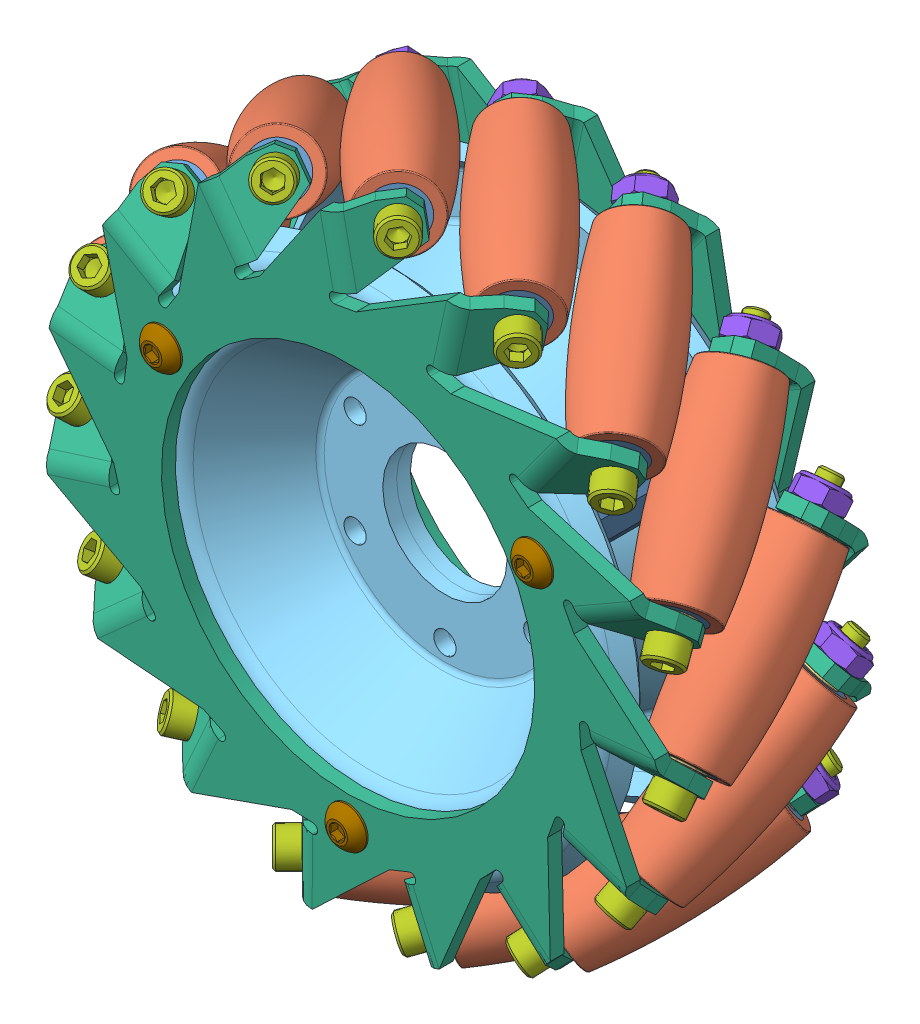
SolidWorks assembly BASE-Mecanum Wheel RIGHT, configuration Default. Lengths in mm.
Overall size (162 161.21 55.95).
134 component instances, 10 part files, 0 mates.
Components (placement in the parent):
- am-3479Ra 6 SR Mecanum Right with Standoffs.STEP-1: am-3479Ra 6 SR Mecanum Right with Standoffs.STEP [Default] at origin size (162 161.21 55.95)
  - am-3479_roller.STEP-1: am-3479_roller.STEP [Default] at (29.7299 -60.2636 1.1233) x (0.762257 -0.31184 0.567204) z (-0.055951 -0.90476 -0.422232) size (19.48 44.35 19.48)
    - am-3698_core PC.STEP-1: am-3698_core PC.STEP [Default] at (-2.9239 1.0394 0.8367) size (14.92 43.18 14.92)
    - am-3698_skin TPU v2.STEP-1: am-3698_skin TPU v2.STEP [Default] at (-2.9239 22.6294 0.8367) x (1 0 0) z (0 1 0) size (19.48 19.48 43.18)
    - am-0603 MBC Bushing MU04TH04.STEP-1: am-0603 MBC Bushing MU04TH04.STEP [Default] at (-2.9239 -20.9316 0.8367) x (0 1 0) z (0 0 1) size (6.35 7.94 7.94)
    - am-0603 MBC Bushing MU04TH04.STEP-2: am-0603 MBC Bushing MU04TH04.STEP [Default] at (-2.9239 16.6604 0.8367) x (0 1 0) z (-0.707574 0 0.70664) size (6.35 7.94 7.94)
    - am-0701a 6IN SR Roller Axle.STEP-1: am-0701a 6IN SR Roller Axle.STEP [Default] at (-2.9239 23.2136 0.8367) x (0 -1 0) z (0 0 1) size (44.35 6.35 6.35)
  - am-3479_roller-1.STEP-1: am-3479_roller-1.STEP [Default] at (2.6482 -67.1458 1.1233) x (0.569519 -0.594918 0.567204) z (-0.419113 -0.803782 -0.422232) size (19.48 44.35 19.48)
    - am-3698_core PC.STEP-1: am-3698_core PC.STEP [Default] at (-2.9239 1.0394 0.8367) size (14.92 43.18 14.92)
    - am-3698_skin TPU v2.STEP-1: am-3698_skin TPU v2.STEP [Default] at (-2.9239 22.6294 0.8367) x (1 0 0) z (0 1 0) size (19.48 19.48 43.18)
    - am-0603 MBC Bushing MU04TH04.STEP-1: am-0603 MBC Bushing MU04TH04.STEP [Default] at (-2.9239 -20.9316 0.8367) x (0 1 0) z (0 0 1) size (6.35 7.94 7.94)
    - am-0603 MBC Bushing MU04TH04.STEP-2: am-0603 MBC Bushing MU04TH04.STEP [Default] at (-2.9239 16.6604 0.8367) x (0 1 0) z (-0.707574 0 0.70664) size (6.35 7.94 7.94)
    - am-0701a 6IN SR Roller Axle.STEP-1: am-0701a 6IN SR Roller Axle.STEP [Default] at (-2.9239 23.2136 0.8367) x (0 -1 0) z (0 0 1) size (44.35 6.35 6.35)
  - am-3479_roller-2.STEP-1: am-3479_roller-2.STEP [Default] at (-24.8914 -62.4179 1.1233) x (0.278307 -0.775129 0.567204) z (-0.709806 -0.563823 -0.422232) size (19.48 44.35 19.48)
    - am-3698_core PC.STEP-1: am-3698_core PC.STEP [Default] at (-2.9239 1.0394 0.8367) size (14.92 43.18 14.92)
    - am-3698_skin TPU v2.STEP-1: am-3698_skin TPU v2.STEP [Default] at (-2.9239 22.6294 0.8367) x (1 0 0) z (0 1 0) size (19.48 19.48 43.18)
    - am-0603 MBC Bushing MU04TH04.STEP-1: am-0603 MBC Bushing MU04TH04.STEP [Default] at (-2.9239 -20.9316 0.8367) x (0 1 0) z (0 0 1) size (6.35 7.94 7.94)
    - am-0603 MBC Bushing MU04TH04.STEP-2: am-0603 MBC Bushing MU04TH04.STEP [Default] at (-2.9239 16.6604 0.8367) x (0 1 0) z (-0.707574 0 0.70664) size (6.35 7.94 7.94)
    - am-0701a 6IN SR Roller Axle.STEP-1: am-0701a 6IN SR Roller Axle.STEP [Default] at (-2.9239 23.2136 0.8367) x (0 -1 0) z (0 0 1) size (44.35 6.35 6.35)
  - am-3479_roller-3.STEP-1: am-3479_roller-3.STEP [Default] at (-48.1271 -46.8973 1.1233) x (-0.061028 -0.821313 0.567204) z (-0.877767 -0.226374 -0.422232) size (19.48 44.35 19.48)
    - am-3698_core PC.STEP-1: am-3698_core PC.STEP [Default] at (-2.9239 1.0394 0.8367) size (14.92 43.18 14.92)
    - am-3698_skin TPU v2.STEP-1: am-3698_skin TPU v2.STEP [Default] at (-2.9239 22.6294 0.8367) x (1 0 0) z (0 1 0) size (19.48 19.48 43.18)
    - am-0603 MBC Bushing MU04TH04.STEP-1: am-0603 MBC Bushing MU04TH04.STEP [Default] at (-2.9239 -20.9316 0.8367) x (0 1 0) z (0 0 1) size (6.35 7.94 7.94)
    - am-0603 MBC Bushing MU04TH04.STEP-2: am-0603 MBC Bushing MU04TH04.STEP [Default] at (-2.9239 16.6604 0.8367) x (0 1 0) z (-0.707574 0 0.70664) size (6.35 7.94 7.94)
    - am-0701a 6IN SR Roller Axle.STEP-1: am-0701a 6IN SR Roller Axle.STEP [Default] at (-2.9239 23.2136 0.8367) x (0 -1 0) z (0 0 1) size (44.35 6.35 6.35)
  - am-3479_roller-4.STEP-1: am-3479_roller-4.STEP [Default] at (-63.0411 -23.2678 1.1233) x (-0.38981 -0.725485 0.567204) z (-0.893955 0.150218 -0.422232) size (19.48 44.35 19.48)
    - am-3698_core PC.STEP-1: am-3698_core PC.STEP [Default] at (-2.9239 1.0394 0.8367) size (14.92 43.18 14.92)
    - am-3698_skin TPU v2.STEP-1: am-3698_skin TPU v2.STEP [Default] at (-2.9239 22.6294 0.8367) x (1 0 0) z (0 1 0) size (19.48 19.48 43.18)
    - am-0603 MBC Bushing MU04TH04.STEP-1: am-0603 MBC Bushing MU04TH04.STEP [Default] at (-2.9239 -20.9316 0.8367) x (0 1 0) z (0 0 1) size (6.35 7.94 7.94)
    - am-0603 MBC Bushing MU04TH04.STEP-2: am-0603 MBC Bushing MU04TH04.STEP [Default] at (-2.9239 16.6604 0.8367) x (0 1 0) z (-0.707574 0 0.70664) size (6.35 7.94 7.94)
    - am-0701a 6IN SR Roller Axle.STEP-1: am-0701a 6IN SR Roller Axle.STEP [Default] at (-2.9239 23.2136 0.8367) x (0 -1 0) z (0 0 1) size (44.35 6.35 6.35)
  - am-3479_roller-5.STEP-1: am-3479_roller-5.STEP [Default] at (-67.0548 4.385 1.1233) x (-0.65119 -0.504213 0.567204) z (-0.755569 0.500835 -0.422232) size (19.48 44.35 19.48)
    - am-3698_core PC.STEP-1: am-3698_core PC.STEP [Default] at (-2.9239 1.0394 0.8367) size (14.92 43.18 14.92)
    - am-3698_skin TPU v2.STEP-1: am-3698_skin TPU v2.STEP [Default] at (-2.9239 22.6294 0.8367) x (1 0 0) z (0 1 0) size (19.48 19.48 43.18)
    - am-0603 MBC Bushing MU04TH04.STEP-1: am-0603 MBC Bushing MU04TH04.STEP [Default] at (-2.9239 -20.9316 0.8367) x (0 1 0) z (0 0 1) size (6.35 7.94 7.94)
    - am-0603 MBC Bushing MU04TH04.STEP-2: am-0603 MBC Bushing MU04TH04.STEP [Default] at (-2.9239 16.6604 0.8367) x (0 1 0) z (-0.707574 0 0.70664) size (6.35 7.94 7.94)
    - am-0701a 6IN SR Roller Axle.STEP-1: am-0701a 6IN SR Roller Axle.STEP [Default] at (-2.9239 23.2136 0.8367) x (0 -1 0) z (0 0 1) size (44.35 6.35 6.35)
  - am-3479_roller-6.STEP-1: am-3479_roller-6.STEP [Default] at (-59.4741 31.2795 1.1233) x (-0.799974 -0.195759 0.567204) z (-0.486539 0.764853 -0.422232) size (19.48 44.35 19.48)
    - am-3698_core PC.STEP-1: am-3698_core PC.STEP [Default] at (-2.9239 1.0394 0.8367) size (14.92 43.18 14.92)
    - am-3698_skin TPU v2.STEP-1: am-3698_skin TPU v2.STEP [Default] at (-2.9239 22.6294 0.8367) x (1 0 0) z (0 1 0) size (19.48 19.48 43.18)
    - am-0603 MBC Bushing MU04TH04.STEP-1: am-0603 MBC Bushing MU04TH04.STEP [Default] at (-2.9239 -20.9316 0.8367) x (0 1 0) z (0 0 1) size (6.35 7.94 7.94)
    - am-0603 MBC Bushing MU04TH04.STEP-2: am-0603 MBC Bushing MU04TH04.STEP [Default] at (-2.9239 16.6604 0.8367) x (0 1 0) z (-0.707574 0 0.70664) size (6.35 7.94 7.94)
    - am-0701a 6IN SR Roller Axle.STEP-1: am-0701a 6IN SR Roller Axle.STEP [Default] at (-2.9239 23.2136 0.8367) x (0 -1 0) z (0 0 1) size (44.35 6.35 6.35)
  - am-3479_roller-7.STEP-1: am-3479_roller-7.STEP [Default] at (-41.6097 52.7655 1.1233) x (-0.810435 0.146544 0.567204) z (-0.133382 0.896621 -0.422232) size (19.48 44.35 19.48)
    - am-3698_core PC.STEP-1: am-3698_core PC.STEP [Default] at (-2.9239 1.0394 0.8367) size (14.92 43.18 14.92)
    - am-3698_skin TPU v2.STEP-1: am-3698_skin TPU v2.STEP [Default] at (-2.9239 22.6294 0.8367) x (1 0 0) z (0 1 0) size (19.48 19.48 43.18)
    - am-0603 MBC Bushing MU04TH04.STEP-1: am-0603 MBC Bushing MU04TH04.STEP [Default] at (-2.9239 -20.9316 0.8367) x (0 1 0) z (0 0 1) size (6.35 7.94 7.94)
    - am-0603 MBC Bushing MU04TH04.STEP-2: am-0603 MBC Bushing MU04TH04.STEP [Default] at (-2.9239 16.6604 0.8367) x (0 1 0) z (-0.707574 0 0.70664) size (6.35 7.94 7.94)
    - am-0701a 6IN SR Roller Axle.STEP-1: am-0701a 6IN SR Roller Axle.STEP [Default] at (-2.9239 23.2136 0.8367) x (0 -1 0) z (0 0 1) size (44.35 6.35 6.35)
  - am-3479_roller-8.STEP-1: am-3479_roller-8.STEP [Default] at (-16.5507 65.1279 1.1233) x (-0.680764 0.463508 0.567204) z (0.242838 0.873356 -0.422232) size (19.48 44.35 19.48)
    - am-3698_core PC.STEP-1: am-3698_core PC.STEP [Default] at (-2.9239 1.0394 0.8367) size (14.92 43.18 14.92)
    - am-3698_skin TPU v2.STEP-1: am-3698_skin TPU v2.STEP [Default] at (-2.9239 22.6294 0.8367) x (1 0 0) z (0 1 0) size (19.48 19.48 43.18)
    - am-0603 MBC Bushing MU04TH04.STEP-1: am-0603 MBC Bushing MU04TH04.STEP [Default] at (-2.9239 -20.9316 0.8367) x (0 1 0) z (0 0 1) size (6.35 7.94 7.94)
    - am-0603 MBC Bushing MU04TH04.STEP-2: am-0603 MBC Bushing MU04TH04.STEP [Default] at (-2.9239 16.6604 0.8367) x (0 1 0) z (-0.707574 0 0.70664) size (6.35 7.94 7.94)
    - am-0701a 6IN SR Roller Axle.STEP-1: am-0701a 6IN SR Roller Axle.STEP [Default] at (-2.9239 23.2136 0.8367) x (0 -1 0) z (0 0 1) size (44.35 6.35 6.35)
  - am-3479_roller-9.STEP-1: am-3479_roller-9.STEP [Default] at (11.3701 66.2291 1.1233) x (-0.433383 0.700327 0.567204) z (0.57707 0.699079 -0.422232) size (19.48 44.35 19.48)
    - am-3698_core PC.STEP-1: am-3698_core PC.STEP [Default] at (-2.9239 1.0394 0.8367) size (14.92 43.18 14.92)
    - am-3698_skin TPU v2.STEP-1: am-3698_skin TPU v2.STEP [Default] at (-2.9239 22.6294 0.8367) x (1 0 0) z (0 1 0) size (19.48 19.48 43.18)
    - am-0603 MBC Bushing MU04TH04.STEP-1: am-0603 MBC Bushing MU04TH04.STEP [Default] at (-2.9239 -20.9316 0.8367) x (0 1 0) z (0 0 1) size (6.35 7.94 7.94)
    - am-0603 MBC Bushing MU04TH04.STEP-2: am-0603 MBC Bushing MU04TH04.STEP [Default] at (-2.9239 16.6604 0.8367) x (0 1 0) z (-0.707574 0 0.70664) size (6.35 7.94 7.94)
    - am-0701a 6IN SR Roller Axle.STEP-1: am-0701a 6IN SR Roller Axle.STEP [Default] at (-2.9239 23.2136 0.8367) x (0 -1 0) z (0 0 1) size (44.35 6.35 6.35)
  - am-3479_roller-10.STEP-1: am-3479_roller-10.STEP [Default] at (37.3249 55.8787 1.1233) x (-0.111067 0.816054 0.567204) z (0.81152 0.403925 -0.422232) size (19.48 44.35 19.48)
    - am-3698_core PC.STEP-1: am-3698_core PC.STEP [Default] at (-2.9239 1.0394 0.8367) size (14.92 43.18 14.92)
    - am-3698_skin TPU v2.STEP-1: am-3698_skin TPU v2.STEP [Default] at (-2.9239 22.6294 0.8367) x (1 0 0) z (0 1 0) size (19.48 19.48 43.18)
    - am-0603 MBC Bushing MU04TH04.STEP-1: am-0603 MBC Bushing MU04TH04.STEP [Default] at (-2.9239 -20.9316 0.8367) x (0 1 0) z (0 0 1) size (6.35 7.94 7.94)
    - am-0603 MBC Bushing MU04TH04.STEP-2: am-0603 MBC Bushing MU04TH04.STEP [Default] at (-2.9239 16.6604 0.8367) x (0 1 0) z (-0.707574 0 0.70664) size (6.35 7.94 7.94)
    - am-0701a 6IN SR Roller Axle.STEP-1: am-0701a 6IN SR Roller Axle.STEP [Default] at (-2.9239 23.2136 0.8367) x (0 -1 0) z (0 0 1) size (44.35 6.35 6.35)
  - am-3479_roller-11.STEP-1: am-3479_roller-11.STEP [Default] at (56.8259 35.8663 1.1233) x (0.230454 0.790677 0.567204) z (0.905652 0.038929 -0.422232) size (19.48 44.35 19.48)
    - am-3698_core PC.STEP-1: am-3698_core PC.STEP [Default] at (-2.9239 1.0394 0.8367) size (14.92 43.18 14.92)
    - am-3698_skin TPU v2.STEP-1: am-3698_skin TPU v2.STEP [Default] at (-2.9239 22.6294 0.8367) x (1 0 0) z (0 1 0) size (19.48 19.48 43.18)
    - am-0603 MBC Bushing MU04TH04.STEP-1: am-0603 MBC Bushing MU04TH04.STEP [Default] at (-2.9239 -20.9316 0.8367) x (0 1 0) z (0 0 1) size (6.35 7.94 7.94)
    - am-0603 MBC Bushing MU04TH04.STEP-2: am-0603 MBC Bushing MU04TH04.STEP [Default] at (-2.9239 16.6604 0.8367) x (0 1 0) z (-0.707574 0 0.70664) size (6.35 7.94 7.94)
    - am-0701a 6IN SR Roller Axle.STEP-1: am-0701a 6IN SR Roller Axle.STEP [Default] at (-2.9239 23.2136 0.8367) x (0 -1 0) z (0 0 1) size (44.35 6.35 6.35)
  - am-3479_roller-12.STEP-1: am-3479_roller-12.STEP [Default] at (66.5012 9.6523 1.1233) x (0.532128 0.628585 0.567204) z (0.843188 -0.332799 -0.422232) size (19.48 44.35 19.48)
    - am-3698_core PC.STEP-1: am-3698_core PC.STEP [Default] at (-2.9239 1.0394 0.8367) size (14.92 43.18 14.92)
    - am-3698_skin TPU v2.STEP-1: am-3698_skin TPU v2.STEP [Default] at (-2.9239 22.6294 0.8367) x (1 0 0) z (0 1 0) size (19.48 19.48 43.18)
    - am-0603 MBC Bushing MU04TH04.STEP-1: am-0603 MBC Bushing MU04TH04.STEP [Default] at (-2.9239 -20.9316 0.8367) x (0 1 0) z (0 0 1) size (6.35 7.94 7.94)
    - am-0603 MBC Bushing MU04TH04.STEP-2: am-0603 MBC Bushing MU04TH04.STEP [Default] at (-2.9239 16.6604 0.8367) x (0 1 0) z (-0.707574 0 0.70664) size (6.35 7.94 7.94)
    - am-0701a 6IN SR Roller Axle.STEP-1: am-0701a 6IN SR Roller Axle.STEP [Default] at (-2.9239 23.2136 0.8367) x (0 -1 0) z (0 0 1) size (44.35 6.35 6.35)
  - am-3479_roller-13.STEP-1: am-3479_roller-13.STEP [Default] at (64.6778 -18.2306 1.1233) x (0.741792 0.357805 0.567204) z (0.634929 -0.646982 -0.422232) size (19.48 44.35 19.48)
    - am-3698_core PC.STEP-1: am-3698_core PC.STEP [Default] at (-2.9239 1.0394 0.8367) size (14.92 43.18 14.92)
    - am-3698_skin TPU v2.STEP-1: am-3698_skin TPU v2.STEP [Default] at (-2.9239 22.6294 0.8367) x (1 0 0) z (0 1 0) size (19.48 19.48 43.18)
    - am-0603 MBC Bushing MU04TH04.STEP-1: am-0603 MBC Bushing MU04TH04.STEP [Default] at (-2.9239 -20.9316 0.8367) x (0 1 0) z (0 0 1) size (6.35 7.94 7.94)
    - am-0603 MBC Bushing MU04TH04.STEP-2: am-0603 MBC Bushing MU04TH04.STEP [Default] at (-2.9239 16.6604 0.8367) x (0 1 0) z (-0.707574 0 0.70664) size (6.35 7.94 7.94)
    - am-0701a 6IN SR Roller Axle.STEP-1: am-0701a 6IN SR Roller Axle.STEP [Default] at (-2.9239 23.2136 0.8367) x (0 -1 0) z (0 0 1) size (44.35 6.35 6.35)
  - am-3479_roller-14.STEP-1: am-3479_roller-14.STEP [Default] at (51.671 -42.9613 1.1233) x (0.823193 0.025157 0.567204) z (0.316885 -0.849296 -0.422232) size (19.48 44.35 19.48)
    - am-3698_core PC.STEP-1: am-3698_core PC.STEP [Default] at (-2.9239 1.0394 0.8367) size (14.92 43.18 14.92)
    - am-3698_skin TPU v2.STEP-1: am-3698_skin TPU v2.STEP [Default] at (-2.9239 22.6294 0.8367) x (1 0 0) z (0 1 0) size (19.48 19.48 43.18)
    - am-0603 MBC Bushing MU04TH04.STEP-1: am-0603 MBC Bushing MU04TH04.STEP [Default] at (-2.9239 -20.9316 0.8367) x (0 1 0) z (0 0 1) size (6.35 7.94 7.94)
    - am-0603 MBC Bushing MU04TH04.STEP-2: am-0603 MBC Bushing MU04TH04.STEP [Default] at (-2.9239 16.6604 0.8367) x (0 1 0) z (-0.707574 0 0.70664) size (6.35 7.94 7.94)
    - am-0701a 6IN SR Roller Axle.STEP-1: am-0701a 6IN SR Roller Axle.STEP [Default] at (-2.9239 23.2136 0.8367) x (0 -1 0) z (0 0 1) size (44.35 6.35 6.35)
  - ip-3479a_hub.STEP-1: ip-3479a_hub.STEP [Default] x (0 0 1) z (1 0 0) size (22.23 118.71 118.71)
  - ip-3479a_hub.STEP-2: ip-3479a_hub.STEP [Default] x (0 0 -1) z (-1 0 0) size (22.23 118.71 118.71)
  - am-0676a Right Plate HD.STEP-1: am-0676a Right Plate HD.STEP [Default] at (0 0 25.4) x (0 0 1) z (0.999437 -0.033548 0) size (13.05 146.22 146.64)
  - am-0676a Right Plate HD.STEP-2: am-0676a Right Plate HD.STEP [Default] at (0 0 -25.4) x (0 0 -1) z (-0.999437 -0.033548 0) size (13.05 146.22 146.64)
  - 10-32x2250_shcs_HX-SHCS 0.19-32x1.375x1-C.STEP-1: 10-32x2250_shcs_HX-SHCS 0.19-32x1.375x1-C.STEP [Default] at (7.2649 -69.1919 21.2501) x (0.644852 0.290113 -0.707107) z (0.436317 -0.899328 0.028925) size (61.98 7.94 7.94)
  - 10-32 Nylock Jam Nut_90633A411.STEP-1: 10-32 Nylock Jam Nut_90633A411.STEP [Default] at (43.1305 -53.0563 -18.0781) x (0.52991 -0.836403 0.140095) z (0.550782 0.465043 0.69309) size (9.55 4.38 11.02)
  - 10-32 Nylock Jam Nut_90633A411.STEP-2: 10-32 Nylock Jam Nut_90633A411.STEP [Default] at (17.8218 -66.0121 -18.0781) x (0.143901 -0.979625 0.140095) z (0.692315 0.200815 0.69309) size (9.55 4.38 11.02)
  - 10-32 Nylock Jam Nut_90633A411.STEP-3: 10-32 Nylock Jam Nut_90633A411.STEP [Default] at (-10.5686 -67.5538 -18.0781) x (-0.266989 -0.953462 0.140095) z (0.71414 -0.098136 0.69309) size (9.55 4.38 11.02)
  - 10-32 Nylock Jam Nut_90633A411.STEP-4: 10-32 Nylock Jam Nut_90633A411.STEP [Default] at (-37.1315 -57.4149 -18.0781) x (-0.631715 -0.762437 0.140095) z (0.612484 -0.380119 0.69309) size (9.55 4.38 11.02)
  - 10-32 Nylock Jam Nut_90633A411.STEP-5: 10-32 Nylock Jam Nut_90633A411.STEP [Default] at (-57.274 -37.3484 -18.0781) x (-0.887211 -0.439579 0.140095) z (0.404923 -0.596376 0.69309) size (9.55 4.38 11.02)
  - 10-32 Nylock Jam Nut_90633A411.STEP-6: 10-32 Nylock Jam Nut_90633A411.STEP [Default] at (-67.5134 -10.824 -18.0781) x (-0.989301 -0.040714 0.140095) z (0.127348 -0.709513 0.69309) size (9.55 4.38 11.02)
  - 10-32 Nylock Jam Nut_90633A411.STEP-7: 10-32 Nylock Jam Nut_90633A411.STEP [Default] at (-66.079 17.572 -18.0781) x (-0.920331 0.365191 0.140095) z (-0.172247 -0.69997 0.69309) size (9.55 4.38 11.02)
  - 10-32 Nylock Jam Nut_90633A411.STEP-8: 10-32 Nylock Jam Nut_90633A411.STEP [Default] at (-53.2191 42.9296 -18.0781) x (-0.692228 0.707951 0.140095) z (-0.442059 -0.569395 0.69309) size (9.55 4.38 11.02)
  - 10-32 Nylock Jam Nut_90633A411.STEP-9: 10-32 Nylock Jam Nut_90633A411.STEP [Default] at (-31.157 60.8642 -18.0781) x (-0.344432 0.9283 0.140095) z (-0.635435 -0.340367 0.69309) size (9.55 4.38 11.02)
  - 10-32 Nylock Jam Nut_90633A411.STEP-10: 10-32 Nylock Jam Nut_90633A411.STEP [Default] at (-3.7076 68.2749 -18.0781) x (0.062919 0.988137 0.140095) z (-0.718938 -0.052486 0.69309) size (9.55 4.38 11.02)
  - 10-32 Nylock Jam Nut_90633A411.STEP-11: 10-32 Nylock Jam Nut_90633A411.STEP [Default] at (24.3828 63.8803 -18.0781) x (0.459391 0.877116 0.140095) z (-0.678131 0.24447 0.69309) size (9.55 4.38 11.02)
  - 10-32 Nylock Jam Nut_90633A411.STEP-12: 10-32 Nylock Jam Nut_90633A411.STEP [Default] at (48.2573 48.4402 -18.0781) x (0.77643 0.614435 0.140095) z (-0.520068 0.499155 0.69309) size (9.55 4.38 11.02)
  - 10-32 Nylock Jam Nut_90633A411.STEP-13: 10-32 Nylock Jam Nut_90633A411.STEP [Default] at (63.7876 24.6243 -18.0781) x (0.959217 0.245511 0.140095) z (-0.272081 0.667532 0.69309) size (9.55 4.38 11.02)
  - 10-32 Nylock Jam Nut_90633A411.STEP-14: 10-32 Nylock Jam Nut_90633A411.STEP [Default] at (68.2885 -3.4494 -18.0781) x (0.976147 -0.165863 0.140095) z (0.022951 0.720486 0.69309) size (9.55 4.38 11.02)
  - 10-32 Nylock Jam Nut_90633A411.STEP-15: 10-32 Nylock Jam Nut_90633A411.STEP [Default] at (60.9816 -30.9266 -18.0781) x (0.824292 -0.548558 0.140095) z (0.314015 0.648862 0.69309) size (9.55 4.38 11.02)
  - 10-32x2250_shcs_HX-SHCS 0.19-32x1.375x1-C.STEP-2: 10-32x2250_shcs_HX-SHCS 0.19-32x1.375x1-C.STEP [Default] at (-21.5061 -66.1649 21.2501) x (0.707101 0.002746 -0.707107) z (0.032806 -0.999043 0.028925) size (61.98 7.94 7.94)
  - 10-32x2250_shcs_HX-SHCS 0.19-32x1.375x1-C.STEP-3: 10-32x2250_shcs_HX-SHCS 0.19-32x1.375x1-C.STEP [Default] at (-46.5585 -51.6973 21.2501) x (0.647086 -0.285095 -0.707107) z (-0.376378 -0.926015 0.028925) size (61.98 7.94 7.94)
  - 10-32x2250_shcs_HX-SHCS 0.19-32x1.375x1-C.STEP-4: 10-32x2250_shcs_HX-SHCS 0.19-32x1.375x1-C.STEP [Default] at (-63.5605 -28.2908 21.2501) x (0.475184 -0.523641 -0.707107) z (-0.720482 -0.69287 0.028925) size (61.98 7.94 7.94)
  - 10-32x2250_shcs_HX-SHCS 0.19-32x1.375x1-C.STEP-5: 10-32x2250_shcs_HX-SHCS 0.19-32x1.375x1-C.STEP [Default] at (-69.5723 0.0074 21.2501) x (0.221118 -0.671645 -0.707107) z (-0.940009 -0.339921 0.028925) size (61.98 7.94 7.94)
  - 10-32x2250_shcs_HX-SHCS 0.19-32x1.375x1-C.STEP-6: 10-32x2250_shcs_HX-SHCS 0.19-32x1.375x1-C.STEP [Default] at (-63.5544 28.3044 21.2501) x (-0.071181 -0.703515 -0.707107) z (-0.996999 0.071802 0.028925) size (61.98 7.94 7.94)
  - 10-32x2250_shcs_HX-SHCS 0.19-32x1.375x1-C.STEP-7: 10-32x2250_shcs_HX-SHCS 0.19-32x1.375x1-C.STEP [Default] at (-46.5474 51.7072 21.2501) x (-0.351172 -0.613741 -0.707107) z (-0.8816 0.471111 0.028925) size (61.98 7.94 7.94)
  - 10-32x2250_shcs_HX-SHCS 0.19-32x1.375x1-C.STEP-8: 10-32x2250_shcs_HX-SHCS 0.19-32x1.375x1-C.STEP [Default] at (-21.4919 66.1695 21.2501) x (-0.570443 -0.417846 -0.707107) z (-0.613763 0.78896 0.028925) size (61.98 7.94 7.94)
  - 10-32x2250_shcs_HX-SHCS 0.19-32x1.375x1-C.STEP-9: 10-32x2250_shcs_HX-SHCS 0.19-32x1.375x1-C.STEP [Default] at (7.2797 69.1904 21.2501) x (-0.691079 -0.149701 -0.707107) z (-0.239802 0.970391 0.028925) size (61.98 7.94 7.94)
  - 10-32x2250_shcs_HX-SHCS 0.19-32x1.375x1-C.STEP-10: 10-32x2250_shcs_HX-SHCS 0.19-32x1.375x1-C.STEP [Default] at (34.7926 60.2476 21.2501) x (-0.692221 0.144328 -0.707107) z (0.175624 0.984032 0.028925) size (61.98 7.94 7.94)
  - 10-32x2250_shcs_HX-SHCS 0.19-32x1.375x1-C.STEP-11: 10-32x2250_shcs_HX-SHCS 0.19-32x1.375x1-C.STEP [Default] at (56.2895 40.8875 21.2501) x (-0.573671 0.413402 -0.707107) z (0.560682 0.827526 0.028925) size (61.98 7.94 7.94)
  - 10-32x2250_shcs_HX-SHCS 0.19-32x1.375x1-C.STEP-12: 10-32x2250_shcs_HX-SHCS 0.19-32x1.375x1-C.STEP [Default] at (68.0535 14.4576 21.2501) x (-0.355929 0.610995 -0.707107) z (0.848794 0.527932 0.028925) size (61.98 7.94 7.94)
  - 10-32x2250_shcs_HX-SHCS 0.19-32x1.375x1-C.STEP-13: 10-32x2250_shcs_HX-SHCS 0.19-32x1.375x1-C.STEP [Default] at (68.0504 -14.4722 21.2501) x (-0.076644 0.702941 -0.707107) z (0.990141 0.137055 0.028925) size (61.98 7.94 7.94)
  - 10-32x2250_shcs_HX-SHCS 0.19-32x1.375x1-C.STEP-14: 10-32x2250_shcs_HX-SHCS 0.19-32x1.375x1-C.STEP [Default] at (56.2808 -40.8996 21.2501) x (0.215894 0.673342 -0.707107) z (0.960284 -0.277521 0.028925) size (61.98 7.94 7.94)
  - 10-32x2250_shcs_HX-SHCS 0.19-32x1.375x1-C.STEP-15: 10-32x2250_shcs_HX-SHCS 0.19-32x1.375x1-C.STEP [Default] at (34.7797 -60.2551 21.2501) x (0.471102 0.527317 -0.707107) z (0.764385 -0.644111 0.028925) size (61.98 7.94 7.94)
  - BHCS 10-32 x 0.625 patch_92360A219.STEP-1: BHCS 10-32 x 0.625 patch_92360A219.STEP [Default] at (0 -49.2125 27.9654) size (9.17 9.17 18.45)
  - BHCS 10-32 x 0.625 patch_92360A219.STEP-2: BHCS 10-32 x 0.625 patch_92360A219.STEP [Default] at (-42.6193 24.6062 27.9654) size (9.17 9.17 18.45)
  - BHCS 10-32 x 0.625 patch_92360A219.STEP-3: BHCS 10-32 x 0.625 patch_92360A219.STEP [Default] at (42.6193 24.6062 27.9654) size (9.17 9.17 18.45)
  - BHCS 10-32 x 0.625 patch_92360A219.STEP-4: BHCS 10-32 x 0.625 patch_92360A219.STEP [Default] at (42.6193 24.6062 -27.9654) x (0.923728 0.383049 0) z (0 0 -1) size (9.17 9.17 18.45)
  - BHCS 10-32 x 0.625 patch_92360A219.STEP-5: BHCS 10-32 x 0.625 patch_92360A219.STEP [Default] at (0 -49.2125 -27.9654) x (0.923728 0.383049 0) z (0 0 -1) size (9.17 9.17 18.45)
  - BHCS 10-32 x 0.625 patch_92360A219.STEP-6: BHCS 10-32 x 0.625 patch_92360A219.STEP [Default] at (-42.6193 24.6062 -27.9654) x (0.923728 0.383049 0) z (0 0 -1) size (9.17 9.17 18.45)
  - 91780A190_ALUM FEM THRDED HEX STANDOFF_91780A190.STEP-1: 91780A190_ALUM FEM THRDED HEX STANDOFF_91780A190.STEP [Default] at (42.6193 24.6062 0) x (0.923728 0.383049 0) z (0 0 -1) size (10.44 13.9 43.26)
  - 91780A190_ALUM FEM THRDED HEX STANDOFF_91780A190.STEP-2: 91780A190_ALUM FEM THRDED HEX STANDOFF_91780A190.STEP [Default] at (0 -49.2125 0) x (0.923728 0.383049 0) z (0 0 -1) size (10.44 13.9 43.26)
  - 91780A190_ALUM FEM THRDED HEX STANDOFF_91780A190.STEP-3: 91780A190_ALUM FEM THRDED HEX STANDOFF_91780A190.STEP [Default] at (-42.6193 24.6062 0) x (0.923728 0.383049 0) z (0 0 -1) size (10.44 13.9 43.26)
